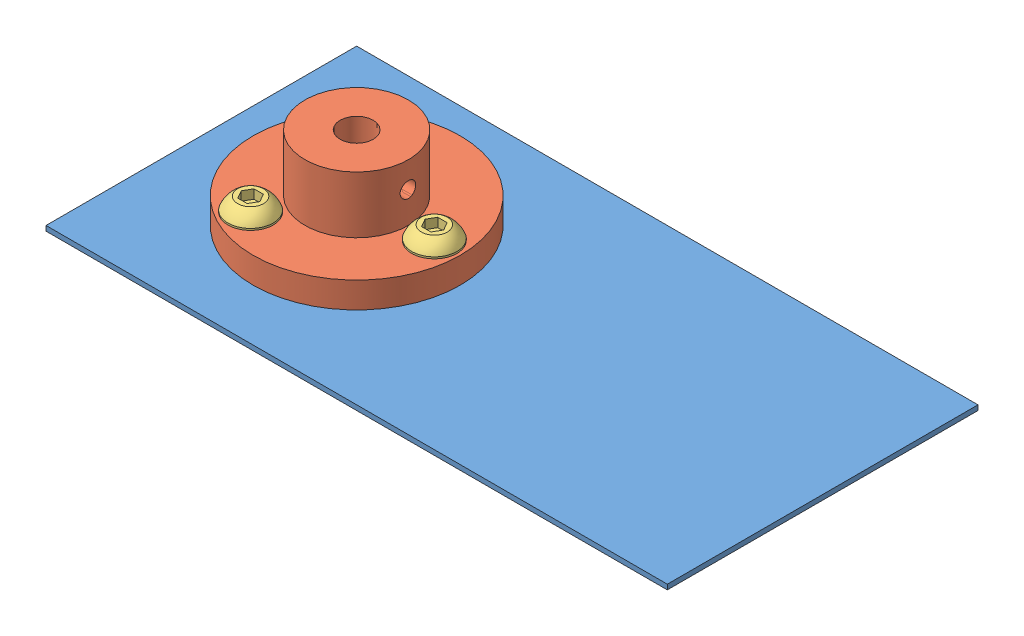
SolidWorks assembly Gate, configuration Gate Assembly. Lengths in mm.
Overall size (152.4 26.67 76.2).
8 component instances, 4 part files, 18 mates.
Components (placement in the parent):
- Dispenser Gate-1: Dispenser Gate [Default] at (-31.0966 74.0903 164.6921) size (152.4 1.22 76.2)
- Gate Hub-1: Gate Hub [Gate Hub] at (7.0034 95.6295 126.5921) x (0 0 -1) z (0 -1 0) size (50.8 50.8 20.32)
- 0.25-20 Button Head Cap Screw (BHCS)-1: 0.25-20 Button Head Cap Screw (BHCS) [Default] at (-2.5216 85.0123 143.0899) x (1 0 0) z (0 -1 0) size (11.1 11.1 16.05)
- 0.25-20 Button Head Cap Screw (BHCS)-2: 0.25-20 Button Head Cap Screw (BHCS) [Default] at (-2.5216 85.0123 110.0943) x (1 0 0) z (0 -1 0) size (11.1 11.1 16.05)
- 0.25-20 Button Head Cap Screw (BHCS)-3: 0.25-20 Button Head Cap Screw (BHCS) [Default] at (26.0534 85.0123 126.5921) x (1 0 0) z (0 -1 0) size (11.1 11.1 16.05)
- 80-20 0.25-20 T-NUT-1: 80-20 0.25-20 T-NUT [Default] at (-120.8742 74.0903 17.1569) x (1 0 0) z (0 -1 0) size (25.4 11.25 2.41)
- 80-20 0.25-20 T-NUT-2: 80-20 0.25-20 T-NUT [Default] at (-120.8742 74.0903 -15.8387) x (1 0 0) z (0 -1 0) size (25.4 11.25 2.41)
- 80-20 0.25-20 T-NUT-3: 80-20 0.25-20 T-NUT [Default] at (-99.8797 74.0903 244.9447) x (0 0 -1) z (0 -1 0) size (25.4 11.25 2.41)
Mates (geometry in assembly coordinates):
- Coincident5: coincident anti-aligned: plane of Dispenser Gate-1 through (-31.0966 75.3095 164.6921) normal (0 1 0); plane of Gate Hub-1 through (32.4034 75.3095 126.5921) normal (0 -1 0)
- Concentric1: concentric aligned: circle of Dispenser Gate-1; circle of Gate Hub-1
- Concentric2: concentric aligned: circle of Dispenser Gate-1; circle of Gate Hub-1
- Coincident8: coincident anti-aligned: plane of Gate Hub-1 through (19.7034 81.6595 126.5921) normal (0 1 0); plane of 0.25-20 Button Head Cap Screw (BHCS)-1 through (3.0283 81.6595 143.0899) normal (0 -1 0)
- Concentric3: concentric aligned: cylinder of Gate Hub-1 through (-2.5216 81.6595 143.0899) axis (0 1 0) radius 3.175; cylinder of 0.25-20 Button Head Cap Screw (BHCS)-1 through (-2.5216 68.9595 143.0899) axis (0 1 0) radius 3.175
- Coincident9: coincident anti-aligned: plane of Gate Hub-1 through (19.7034 81.6595 126.5921) normal (0 1 0); plane of 0.25-20 Button Head Cap Screw (BHCS)-2 through (3.0283 81.6595 110.0943) normal (0 -1 0)
- Concentric4: concentric aligned: circle of Dispenser Gate-1; cylinder of 0.25-20 Button Head Cap Screw (BHCS)-2 through (-2.5216 68.9595 110.0943) axis (0 1 0) radius 3.175
- Coincident11: coincident anti-aligned: plane of Gate Hub-1 through (19.7034 81.6595 126.5921) normal (0 1 0); plane of 0.25-20 Button Head Cap Screw (BHCS)-3 through (31.6033 81.6595 126.5921) normal (0 -1 0)
- Concentric5: concentric aligned: circle of Gate Hub-1; cylinder of 0.25-20 Button Head Cap Screw (BHCS)-3 through (26.0534 68.9595 126.5921) axis (0 1 0) radius 3.175
- Coincident13: coincident anti-aligned: plane of Dispenser Gate-1 through (-31.0966 74.0903 164.6921) normal (0 -1 0); plane of 80-20 0.25-20 T-NUT-1 through (-9.5955 74.0903 143.0899) normal (0 1 0)
- Concentric6: concentric anti-aligned: cylinder of 0.25-20 Button Head Cap Screw (BHCS)-1 through (-2.5216 68.9595 143.0899) axis (0 1 0) radius 3.175; cylinder of 80-20 0.25-20 T-NUT-1 through (-2.5216 74.0913 143.0899) axis (0 -1 0) radius 3.175
- Coincident14: coincident anti-aligned: plane of Dispenser Gate-1 through (-31.0966 74.0903 164.6921) normal (0 -1 0); plane of 80-20 0.25-20 T-NUT-2 through (-9.5955 74.0903 110.0943) normal (0 1 0)
- Concentric7: concentric anti-aligned: cylinder of 0.25-20 Button Head Cap Screw (BHCS)-2 through (-2.5216 68.9595 110.0943) axis (0 1 0) radius 3.175; cylinder of 80-20 0.25-20 T-NUT-2 through (-2.5216 74.0913 110.0943) axis (0 -1 0) radius 3.175
- Coincident15: coincident anti-aligned: plane of Dispenser Gate-1 through (-31.0966 74.0903 164.6921) normal (0 -1 0); plane of 80-20 0.25-20 T-NUT-3 through (26.0534 74.0903 133.666) normal (0 1 0)
- Concentric8: concentric anti-aligned: cylinder of 0.25-20 Button Head Cap Screw (BHCS)-3 through (26.0534 68.9595 126.5921) axis (0 1 0) radius 3.175; cylinder of 80-20 0.25-20 T-NUT-3 through (26.0534 74.0913 126.5921) axis (0 -1 0) radius 3.175
- Parallel2: parallel: line of Dispenser Gate-1 through (-31.0966 75.3095 88.4921) axis (0 0 1); plane of 80-20 0.25-20 T-NUT-3 through (20.4273 71.6773 133.666) normal (-1 0 0)
- Perpendicular2: perpendicular: line of Dispenser Gate-1 through (-31.0966 74.0903 88.4921) axis (0 0 1); plane of 80-20 0.25-20 T-NUT-2 through (-9.5955 71.6773 115.7204) normal (0 0 1)
- Perpendicular3: perpendicular: line of Dispenser Gate-1 through (-31.0966 74.0903 88.4921) axis (0 0 1); line of 80-20 0.25-20 T-NUT-1 through (4.5523 71.6773 148.716) axis (-1 0 0)
